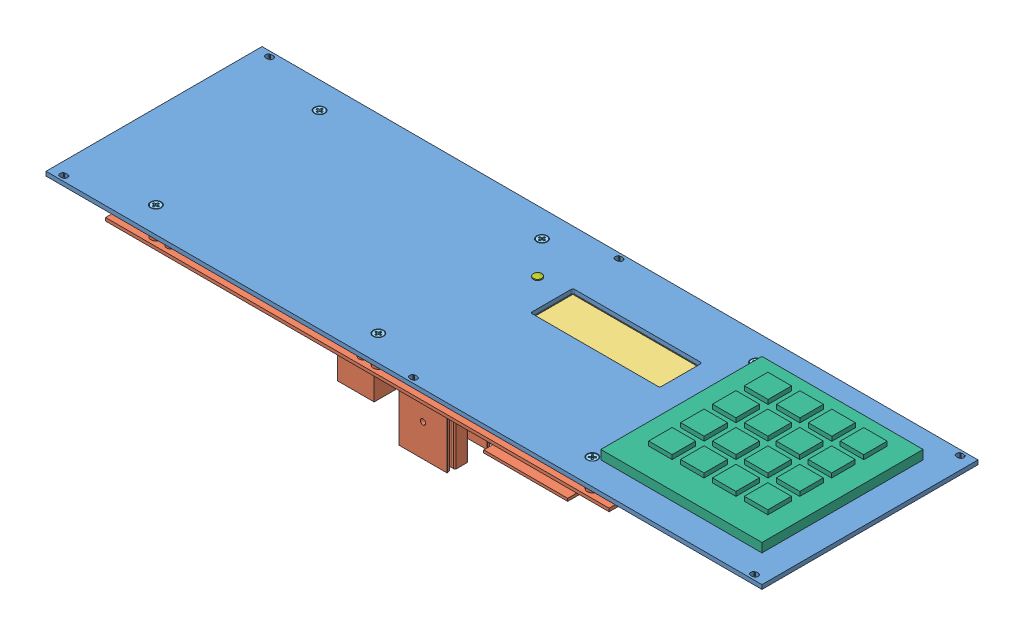
SolidWorks assembly MLA-0387-M5, configuration Default. Lengths in mm.
Overall size (426.52 63.69 128.7).
20 component instances, 9 part files, 41 mates.
Components (placement in the parent):
- MLA-0387-M1-1: MLA-0387-M1 [Default] at (-31.2027 -157.9839 598.0559) size (426.52 2.5 128.7)
- MLA-0387-P1-PB1-3: MLA-0387-P1-PB1 [Default] at (-3.4827 205.6061 369.0559) x (1 0 0) z (0 1 0) size (300 107.5 53.19)
- NHD-0420D3Z-FL-GBW-V3-1: NHD-0420D3Z-FL-GBW-V3 [Default] at (178.2673 208.6161 325.5559) x (1 0 0) z (0 1 0) size (98 60 10.6)
- pan_head_phillip_M2x4-1: pan_head_phillip_M2x4 [Default] at (180.7673 210.2161 268.0559) x (1 0 0) z (0 0 1) size (4 9.78 4)
- pan_head_phillip_M2x4-2: pan_head_phillip_M2x4 [Default] at (273.7673 210.2161 268.0559) x (1 0 0) z (0 0 1) size (4 9.78 4)
- pan_head_phillip_M2x4-3: pan_head_phillip_M2x4 [Default] at (273.7674 210.2161 323.0559) x (1 0 0) z (0 0 1) size (4 9.78 4)
- pan_head_phillip_M2x4-4: pan_head_phillip_M2x4 [Default] at (180.7673 210.2161 323.0559) x (1 0 0) z (0 0 1) size (4 9.78 4)
- SCREW_ISO 7046-1: SCREW_ISO 7046 [VIJAK M 3x 10] at (21.5173 222.1161 266.5559) x (0 -1 0) z (0 0 1) size (10 5.6 5.6)
- SCREW_ISO 7046-2: SCREW_ISO 7046 [VIJAK M 3x 10] at (21.5173 222.1161 364.0559) x (0 -1 0) z (1 0 0) size (10 5.6 5.6)
- SCREW_ISO 7046-3: SCREW_ISO 7046 [VIJAK M 3x 10] at (154.0173 222.1161 364.0559) x (0 -1 0) z (0 0 1) size (10 5.6 5.6)
- SCREW_ISO 7046-4: SCREW_ISO 7046 [VIJAK M 3x 10] at (154.0173 222.1161 266.5559) x (0 -1 0) z (0 0 1) size (10 5.6 5.6)
- SCREW_ISO 7046-5: SCREW_ISO 7046 [VIJAK M 3x 10] at (281.5173 222.1161 266.5559) x (0 -1 0) z (0 0 1) size (10 5.6 5.6)
- SCREW_ISO 7046-6: SCREW_ISO 7046 [VIJAK M 3x 10] at (281.5173 221.9757 364.0559) x (0 -1 0) z (-0.743067 0 0.669217) size (10 5.6 5.6)
- Storm_7016010-2: Storm_7016010 [Default] at (285.6073 222.1161 363.1059) x (1 0 0) z (0 1 0) size (96 96 22)
- PLW5-500-1: PLW5-500 [Default] at (172.5173 222.1161 287.6459) size (5.25 13.97 5.07)
- MLA-0387-M7-1: MLA-0387-M7 [Default] at (25.5172 213.6161 369.056) x (1 0 0) z (0 0 1) size (124.5 3 107.5)
- M2_5x8_Pan_head-1: M2_5x8_Pan_head [Default] at (30.5172 216.6161 266.556) x (0 -1 0) z (-0.546944 0 0.837169) size (13.3 7.99 5.14)
- M2_5x8_Pan_head-2: M2_5x8_Pan_head [Default] at (30.5172 216.6161 364.056) x (0 -1 0) z (-0.546944 0 0.837169) size (13.3 7.99 5.14)
- M2_5x8_Pan_head-3: M2_5x8_Pan_head [Default] at (145.0172 216.6161 266.556) x (0 -1 0) z (-0.546944 0 0.837169) size (13.3 7.99 5.14)
- M2_5x8_Pan_head-4: M2_5x8_Pan_head [Default] at (145.0172 216.6161 364.056) x (0 -1 0) z (-0.546944 0 0.837169) size (13.3 7.99 5.14)
Mates (geometry in assembly coordinates):
- Concentric30: concentric aligned: cone of MLA-0387-M1-1 through (21.5173 222.1161 266.5559) axis (0 -1 0); cone of SCREW_ISO 7046-1 through (21.5173 220.6161 266.5559) axis (0 -1 0)
- Coincident48: coincident aligned: plane of MLA-0387-M1-1 through (-23.1223 222.1161 294.98) normal (0 1 0); plane of SCREW_ISO 7046-1 through (21.5173 222.1161 266.5559) normal (0 1 0)
- Concentric31: concentric aligned: cone of MLA-0387-M1-1 through (21.5173 222.1161 364.0559) axis (0 -1 0); cone of SCREW_ISO 7046-2 through (21.5173 220.6161 364.0559) axis (0 -1 0)
- Coincident49: coincident aligned: plane of MLA-0387-M1-1 through (-23.1223 222.1161 294.98) normal (0 1 0); plane of SCREW_ISO 7046-2 through (21.5173 222.1161 364.0559) normal (0 1 0)
- Concentric32: concentric aligned: cone of MLA-0387-M1-1 through (154.0173 222.1161 364.0559) axis (0 -1 0); cone of SCREW_ISO 7046-3 through (154.0173 220.6161 364.0559) axis (0 -1 0)
- Coincident50: coincident aligned: plane of MLA-0387-M1-1 through (-23.1223 222.1161 294.98) normal (0 1 0); plane of SCREW_ISO 7046-3 through (154.0173 222.1161 364.0559) normal (0 1 0)
- Concentric33: concentric aligned: cone of MLA-0387-M1-1 through (154.0173 222.1161 266.5559) axis (0 -1 0); cone of SCREW_ISO 7046-4 through (154.0173 220.6161 266.5559) axis (0 -1 0)
- Coincident51: coincident aligned: plane of MLA-0387-M1-1 through (-23.1223 222.1161 294.98) normal (0 1 0); plane of SCREW_ISO 7046-4 through (154.0173 222.1161 266.5559) normal (0 1 0)
- Concentric34: concentric aligned: cone of MLA-0387-M1-1 through (281.5173 222.1161 266.5559) axis (0 -1 0); cone of SCREW_ISO 7046-5 through (281.5173 220.6161 266.5559) axis (0 -1 0)
- Coincident52: coincident aligned: plane of MLA-0387-M1-1 through (-23.1223 222.1161 294.98) normal (0 1 0); plane of SCREW_ISO 7046-5 through (281.5173 222.1161 266.5559) normal (0 1 0)
- Coincident53: coincident: circle of MLA-0387-M1-1; cone of SCREW_ISO 7046-6 through (281.5173 220.4757 364.0559) axis (0 -1 0)
- Concentric36: concentric aligned: cylinder of MLA-0387-M1-1 through (154.0173 222.1161 266.5559) axis (0 -1 0) radius 1.75; cylinder of MLA-0387-P1-PB1-3 through (154.0173 213.2161 266.5559) axis (0 -1 0) radius 3
- Concentric37: concentric aligned: circle of MLA-0387-M1-1; circle of MLA-0387-P1-PB1-3
- Coincident55: coincident anti-aligned: plane of MLA-0387-M1-1 through (-23.1223 219.6161 294.98) normal (0 -1 0); plane of MLA-0387-P1-PB1-3 through (154.0173 219.6161 266.5559) normal (0 1 0)
- Concentric38: concentric aligned: cylinder of MLA-0387-P1-PB1-3 through (180.7673 204.2161 268.0559) axis (0 1 0) radius 2.175; cylinder of NHD-0420D3Z-FL-GBW-V3-1 through (180.7673 208.6161 268.0559) axis (0 1 0) radius 1.25
- Coincident57: coincident aligned: circle of MLA-0387-P1-PB1-3; plane of NHD-0420D3Z-FL-GBW-V3-1 through (178.2673 208.6161 325.5559) normal (0 -1 0)
- Concentric40: concentric aligned: cylinder of MLA-0387-P1-PB1-3 through (273.7673 204.2161 268.0559) axis (0 1 0) radius 2.175; cylinder of NHD-0420D3Z-FL-GBW-V3-1 through (273.7673 208.6161 268.0559) axis (0 1 0) radius 1.25
- Concentric41: concentric anti-aligned: cylinder of MLA-0387-P1-PB1-3 through (180.7673 204.2161 268.0559) axis (0 1 0) radius 2.175; cylinder of pan_head_phillip_M2x4-1 through (180.7673 212.0011 268.0559) axis (0 -1 0) radius 2
- Coincident58: coincident anti-aligned: plane of NHD-0420D3Z-FL-GBW-V3-1 through (178.2673 210.2161 325.5559) normal (0 1 0); plane of pan_head_phillip_M2x4-1 through (180.7673 210.2161 268.0559) normal (0 -1 0)
- Concentric42: concentric anti-aligned: cylinder of MLA-0387-P1-PB1-3 through (273.7673 204.2161 268.0559) axis (0 1 0) radius 2.175; cylinder of pan_head_phillip_M2x4-2 through (273.7673 212.0011 268.0559) axis (0 -1 0) radius 2
- Coincident59: coincident anti-aligned: plane of NHD-0420D3Z-FL-GBW-V3-1 through (178.2673 210.2161 325.5559) normal (0 1 0); plane of pan_head_phillip_M2x4-2 through (273.7673 210.2161 268.0559) normal (0 -1 0)
- Concentric43: concentric anti-aligned: cylinder of MLA-0387-P1-PB1-3 through (273.7674 204.2161 323.0559) axis (0 1 0) radius 2.175; cylinder of pan_head_phillip_M2x4-3 through (273.7674 212.0011 323.0559) axis (0 -1 0) radius 2
- Coincident60: coincident anti-aligned: plane of NHD-0420D3Z-FL-GBW-V3-1 through (178.2673 210.2161 325.5559) normal (0 1 0); plane of pan_head_phillip_M2x4-3 through (273.7674 210.2161 323.0559) normal (0 -1 0)
- Concentric44: concentric anti-aligned: cylinder of MLA-0387-P1-PB1-3 through (180.7673 204.2161 323.0559) axis (0 1 0) radius 2.175; cylinder of pan_head_phillip_M2x4-4 through (180.7673 212.0011 323.0559) axis (0 -1 0) radius 2
- Coincident61: coincident anti-aligned: plane of NHD-0420D3Z-FL-GBW-V3-1 through (178.2673 210.2161 325.5559) normal (0 1 0); plane of pan_head_phillip_M2x4-4 through (180.7673 210.2161 323.0559) normal (0 -1 0)
- Concentric45: concentric anti-aligned: cylinder of MLA-0387-M1-1 through (301.6073 222.1161 283.1059) axis (0 -1 0) radius 1.75; cylinder of Storm_7016010-2 through (301.6073 208.1161 283.1059) axis (0 1 0) radius 1.5
- Concentric46: concentric anti-aligned: cylinder of MLA-0387-M1-1 through (365.6073 222.1161 347.1059) axis (0 -1 0) radius 1.75; cylinder of Storm_7016010-2 through (365.6073 208.1161 347.1059) axis (0 1 0) radius 1.5
- Coincident62: coincident anti-aligned: plane of MLA-0387-M1-1 through (-23.1223 222.1161 294.98) normal (0 1 0); plane of Storm_7016010-2 through (285.6073 222.1161 363.1059) normal (0 -1 0)
- Coincident63: coincident anti-aligned: plane of MLA-0387-M1-1 through (-23.1223 222.1161 294.98) normal (0 1 0); plane of PLW5-500-1 through (169.9854 222.1161 285.1139) normal (0 -1 0)
- Concentric47: concentric aligned: circle of MLA-0387-M1-1; cylinder of PLW5-500-1 through (172.5173 210.6017 287.6459) axis (0 1 0) radius 1.9304
- Concentric48: concentric: cylinder of MLA-0387-P1-PB1-3 through (30.5172 201.7679 266.556) axis (0 -1 0) radius 1.0065; cylinder of MLA-0387-M7-1 through (30.5172 213.6161 266.556) axis (0 1 0) radius 1.5
- Concentric49: concentric: cylinder of MLA-0387-P1-PB1-3 through (145.0172 201.7679 364.056) axis (0 -1 0) radius 1.0065; cylinder of MLA-0387-M7-1 through (145.0172 213.6161 364.056) axis (0 1 0) radius 1.5
- Coincident64: coincident anti-aligned: plane of MLA-0387-P1-PB1-3 through (147.5672 213.6161 364.056) normal (0 1 0); plane of MLA-0387-M7-1 through (25.5172 213.6161 369.056) normal (0 -1 0)
- Concentric50: concentric: cylinder of MLA-0387-M7-1 through (30.5172 213.6161 266.556) axis (0 1 0) radius 1.5; cylinder of M2_5x8_Pan_head-1 through (30.5172 211.1753 266.556) axis (0 1 0) radius 1
- Coincident65: coincident anti-aligned: plane of MLA-0387-M7-1 through (25.5172 216.6161 369.056) normal (0 1 0); plane of M2_5x8_Pan_head-1 through (31.4981 216.6161 265.0545) normal (0 -1 0)
- Concentric51: concentric: cylinder of MLA-0387-M7-1 through (30.5172 213.6161 364.056) axis (0 1 0) radius 1.5; cylinder of M2_5x8_Pan_head-2 through (30.5172 211.1753 364.056) axis (0 1 0) radius 1
- Coincident66: coincident anti-aligned: plane of MLA-0387-M7-1 through (25.5172 216.6161 369.056) normal (0 1 0); plane of M2_5x8_Pan_head-2 through (31.4981 216.6161 362.5545) normal (0 -1 0)
- Concentric52: concentric: cylinder of MLA-0387-M7-1 through (145.0172 213.6161 266.556) axis (0 1 0) radius 1.5; cylinder of M2_5x8_Pan_head-3 through (145.0172 211.1753 266.556) axis (0 1 0) radius 1
- Coincident67: coincident anti-aligned: plane of MLA-0387-M7-1 through (25.5172 216.6161 369.056) normal (0 1 0); plane of M2_5x8_Pan_head-3 through (145.9981 216.6161 265.0545) normal (0 -1 0)
- Concentric53: concentric: cylinder of MLA-0387-M7-1 through (145.0172 213.6161 364.056) axis (0 1 0) radius 1.5; cylinder of M2_5x8_Pan_head-4 through (145.0172 211.1753 364.056) axis (0 1 0) radius 1
- Coincident68: coincident anti-aligned: plane of MLA-0387-M7-1 through (25.5172 216.6161 369.056) normal (0 1 0); plane of M2_5x8_Pan_head-4 through (145.9981 216.6161 362.5545) normal (0 -1 0)
